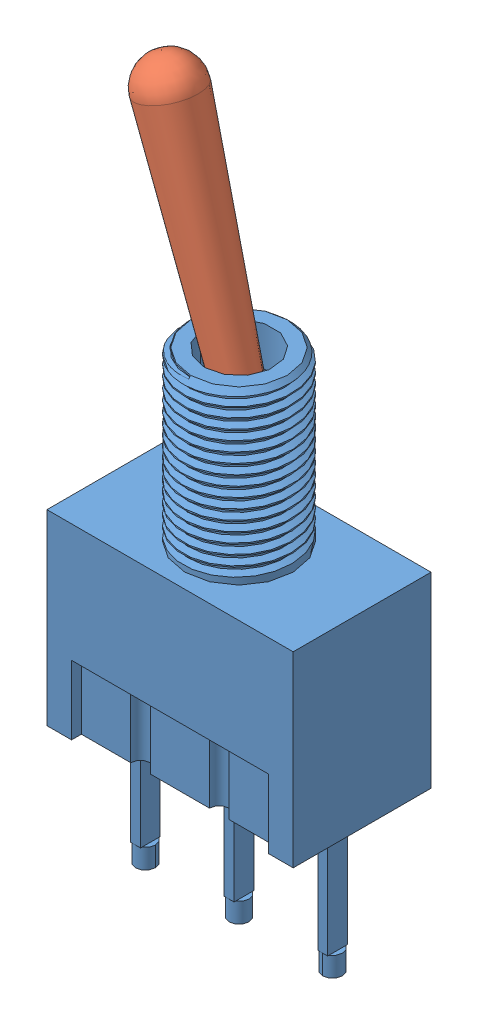
SolidWorks assembly toggle_mts1_assembly, configuration Default. Lengths in mm.
Overall size (12.5 36.55 7).
2 component instances, 2 part files, 7 mates.
Components (placement in the parent):
- toggle_mts_1_base_thread-1: toggle_mts_1_base_thread [Default] at origin size (12.5 25.17 7)
- toggle_mts_1_lever-1: toggle_mts_1_lever [Default] at (0 16.1983 -0.4087) x (0 0 1) z (-0.956305 -0.292372 0) size (3 13.5 3)
Mates (geometry in assembly coordinates):
- Screw1: screw = 0.5 aligned: line of toggle_mts_1_base_thread-1 through (0 17.7 -0.4087) axis (0 -1 0); line of toggle_mts_1_nut-1 through (0 17.1967 -0.4087) axis (0 -1 0)
- Coincident2: coincident anti-aligned: line of toggle_mts_1_base_thread-1 through (0 16.1983 0) axis (0 0 -1); line of toggle_mts_1_lever-1 through (0 16.1983 -1.4087) axis (0 0 1)
- Coincident3: coincident: line of toggle_mts_1_lever-1 through (-3.5085 27.6739 -0.4087) axis (0.292372 -0.956305 0)
- LimitAngle2: limit planar angle = 0.296706 rad aligned: line of toggle_mts_1_lever-1 through (-3.5085 27.6739 -0.4087) axis (0.292372 -0.956305 0); line of toggle_mts_1_base_thread-1 through (0 17.7 -0.4087) axis (0 -1 0)
- Concentric1: concentric aligned: cylinder of toggle_mts_1_base_thread-1 through (0 18 -0.4087) axis (0 -1 0) radius 2.75; cylinder of toggle_mts_1_washer-1 through (0 15.8967 -0.4087) axis (0 -1 0) radius 2.85
- Coincident6: coincident anti-aligned: plane of toggle_mts_1_nut-1 through (0 15.8967 -0.4087) normal (0 -1 0); plane of toggle_mts_1_washer-1 through (0 15.8967 -0.4087) normal (0 1 0)
- LimitDistance1: limit distance = 5.8967 mm anti-aligned: plane of toggle_mts_1_washer-1 through (0 15.3967 -0.4087) normal (0 -1 0); plane of toggle_mts_1_base_thread-1 through (0 9.5 0) normal (0 1 0)
